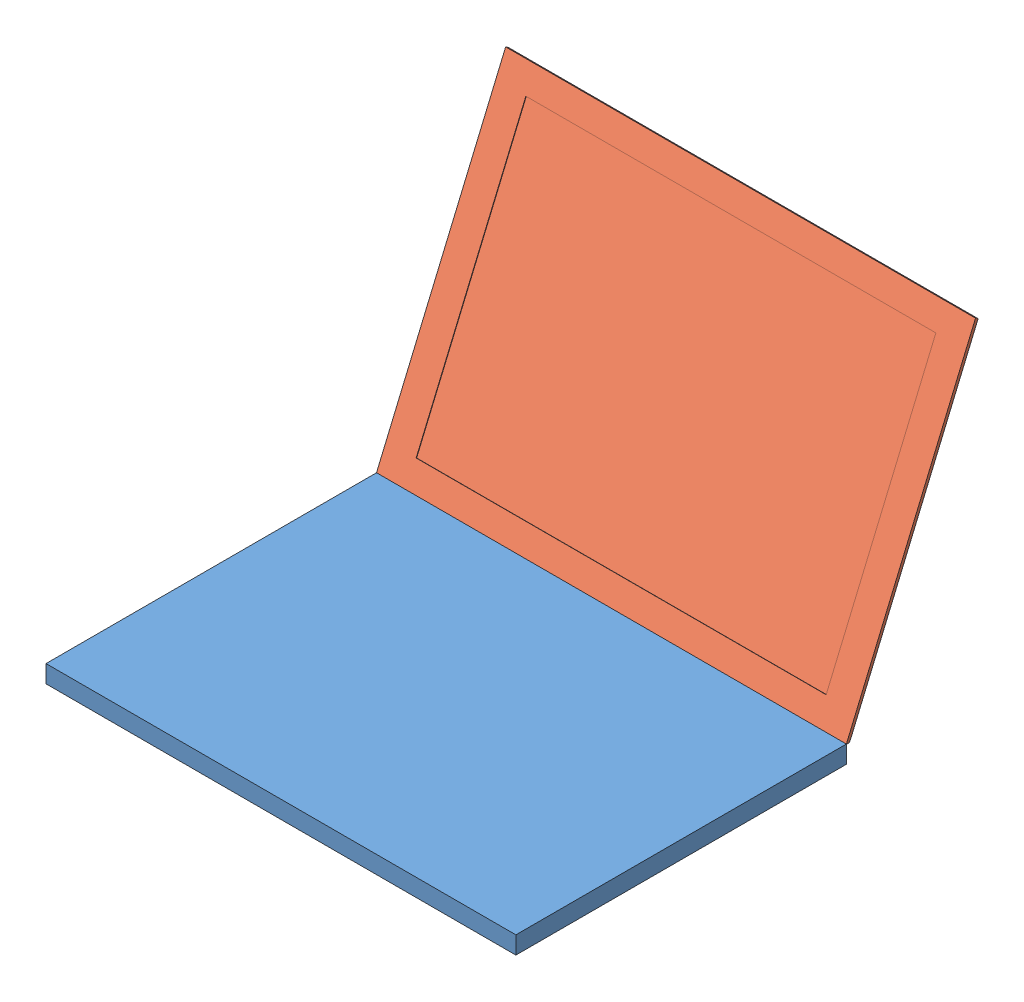
SolidWorks assembly Laptop Assembly, configuration Default. Lengths in mm.
Overall size (374.65 256.58 373.39).
2 component instances, 2 part files, 2 mates.
Components (placement in the parent):
- Laptop Keyboard-1: Laptop Keyboard [Default] at (150.5107 168.6549 300.1957) size (374.65 14 263.53)
- Laptop Screen-1: Laptop Screen [Default] at (150.5116 301.0141 110.0491) x (1 0 0) z (0 -0.920516 0.390704) size (374.65 7.5 263.53)
Mates (geometry in assembly coordinates):
- Coincident3: coincident anti-aligned: line of Laptop Keyboard-1 through (337.8357 182.6549 168.4332) axis (-1 0 0); line of Laptop Screen-1 through (-36.8134 182.6549 168.4332) axis (1 0 0)
- Tangent2: tangent aligned: plane of Laptop Keyboard-1 through (-36.8143 182.6549 431.9582) normal (-1 0 0); cylinder of Laptop Screen-1 through (-29.1943 182.7018 168.5436) axis (0 0.920516 -0.390704) radius 7.62
